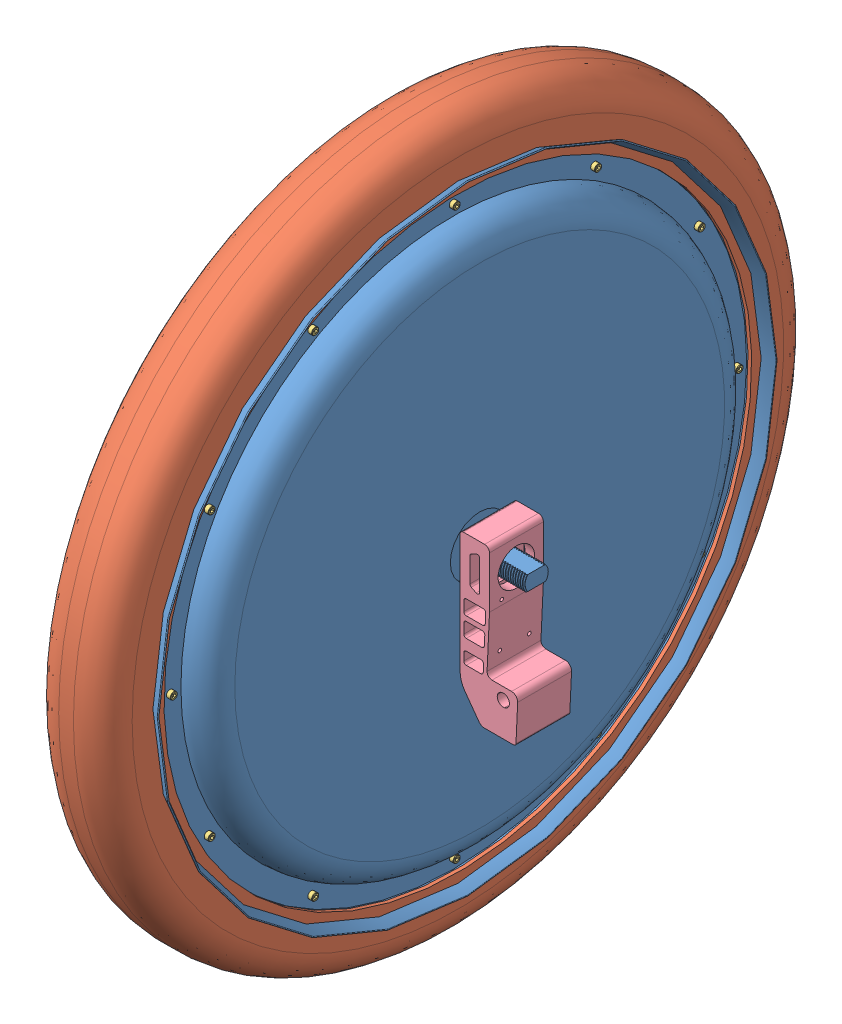
SolidWorks assembly wheel, configuration Default. Lengths in mm.
Overall size (217.51 810.04 810.04).
28 component instances, 5 part files, 9 mates.
Components (placement in the parent):
- motor-1: motor [Default] at origin size (188.73 505.83 505.83)
- tyre-1: tyre [Default] at (-29.8207 0 0) x (1 0 0) z (0 0.587098 0.809516) size (60 580 580)
- socket head cap screw_ai-1: socket head cap screw_ai [HX-SHCS 0.138-40x0.188x0.188-N] at (29.5052 231 0) x (-1 0 0) z (0 0 -1) size (8.28 5.74 5.74)
- socket head cap screw_ai-2: socket head cap screw_ai [HX-SHCS 0.138-40x0.188x0.188-N] at (29.5052 200.0519 -115.5) x (-1 0 0) z (0 -0.5 -0.866025) size (8.28 5.74 5.74)
- socket head cap screw_ai-3: socket head cap screw_ai [HX-SHCS 0.138-40x0.188x0.188-N] at (29.5052 200.0519 115.5) x (-1 0 0) z (0 0.5 -0.866025) size (8.28 5.74 5.74)
- socket head cap screw_ai-4: socket head cap screw_ai [HX-SHCS 0.138-40x0.188x0.188-N] at (29.5052 115.5 200.0519) x (-1 0 0) z (0 0.866025 -0.5) size (8.28 5.74 5.74)
- socket head cap screw_ai-5: socket head cap screw_ai [HX-SHCS 0.138-40x0.188x0.188-N] at (29.5052 0 231) x (-1 0 0) z (0 1 0) size (8.28 5.74 5.74)
- socket head cap screw_ai-6: socket head cap screw_ai [HX-SHCS 0.138-40x0.188x0.188-N] at (29.5052 -115.5 200.0519) x (-1 0 0) z (0 0.866025 0.5) size (8.28 5.74 5.74)
- socket head cap screw_ai-7: socket head cap screw_ai [HX-SHCS 0.138-40x0.188x0.188-N] at (29.5052 -200.0519 115.5) x (-1 0 0) z (0 0.5 0.866025) size (8.28 5.74 5.74)
- socket head cap screw_ai-8: socket head cap screw_ai [HX-SHCS 0.138-40x0.188x0.188-N] at (29.5052 -231 0) x (-1 0 0) z (0 0 1) size (8.28 5.74 5.74)
- socket head cap screw_ai-9: socket head cap screw_ai [HX-SHCS 0.138-40x0.188x0.188-N] at (29.5052 -200.0519 -115.5) x (-1 0 0) z (0 -0.5 0.866025) size (8.28 5.74 5.74)
- socket head cap screw_ai-10: socket head cap screw_ai [HX-SHCS 0.138-40x0.188x0.188-N] at (29.5052 -115.5 -200.0519) x (-1 0 0) z (0 -0.866025 0.5) size (8.28 5.74 5.74)
- socket head cap screw_ai-11: socket head cap screw_ai [HX-SHCS 0.138-40x0.188x0.188-N] at (29.5052 0 -231) x (-1 0 0) z (0 -1 0) size (8.28 5.74 5.74)
- socket head cap screw_ai-12: socket head cap screw_ai [HX-SHCS 0.138-40x0.188x0.188-N] at (29.5052 115.5 -200.0519) x (-1 0 0) z (0 -0.866025 -0.5) size (8.28 5.74 5.74)
- socket head cap screw_ai-13: socket head cap screw_ai [HX-SHCS 0.138-40x0.188x0.188-N] at (-29.5052 231 0) size (8.28 5.74 5.74)
- socket head cap screw_ai-14: socket head cap screw_ai [HX-SHCS 0.138-40x0.188x0.188-N] at (-29.5052 200.0519 -115.5) x (1 0 0) z (0 0.5 0.866025) size (8.28 5.74 5.74)
- socket head cap screw_ai-15: socket head cap screw_ai [HX-SHCS 0.138-40x0.188x0.188-N] at (-29.5052 200.0519 115.5) x (1 0 0) z (0 -0.5 0.866025) size (8.28 5.74 5.74)
- socket head cap screw_ai-16: socket head cap screw_ai [HX-SHCS 0.138-40x0.188x0.188-N] at (-29.5052 115.5 200.0519) x (1 0 0) z (0 -0.866025 0.5) size (8.28 5.74 5.74)
- socket head cap screw_ai-17: socket head cap screw_ai [HX-SHCS 0.138-40x0.188x0.188-N] at (-29.5052 0 231) x (1 0 0) z (0 -1 0) size (8.28 5.74 5.74)
- socket head cap screw_ai-18: socket head cap screw_ai [HX-SHCS 0.138-40x0.188x0.188-N] at (-29.5052 -115.5 200.0519) x (1 0 0) z (0 -0.866025 -0.5) size (8.28 5.74 5.74)
- socket head cap screw_ai-19: socket head cap screw_ai [HX-SHCS 0.138-40x0.188x0.188-N] at (-29.5052 -200.0519 115.5) x (1 0 0) z (0 -0.5 -0.866025) size (8.28 5.74 5.74)
- socket head cap screw_ai-20: socket head cap screw_ai [HX-SHCS 0.138-40x0.188x0.188-N] at (-29.5052 -231 0) x (1 0 0) z (0 0 -1) size (8.28 5.74 5.74)
- socket head cap screw_ai-21: socket head cap screw_ai [HX-SHCS 0.138-40x0.188x0.188-N] at (-29.5052 -200.0519 -115.5) x (1 0 0) z (0 0.5 -0.866025) size (8.28 5.74 5.74)
- socket head cap screw_ai-22: socket head cap screw_ai [HX-SHCS 0.138-40x0.188x0.188-N] at (-29.5052 -115.5 -200.0519) x (1 0 0) z (0 0.866025 -0.5) size (8.28 5.74 5.74)
- socket head cap screw_ai-23: socket head cap screw_ai [HX-SHCS 0.138-40x0.188x0.188-N] at (-29.5052 0 -231) x (1 0 0) z (0 1 0) size (8.28 5.74 5.74)
- socket head cap screw_ai-24: socket head cap screw_ai [HX-SHCS 0.138-40x0.188x0.188-N] at (-29.5052 115.5 -200.0519) x (1 0 0) z (0 0.866025 0.5) size (8.28 5.74 5.74)
- pedal hanger1-1: pedal hanger1 [Default] at (128.9328 -140.4403 -75.0082) x (0.997537 -0.070149 0) z (-0.006861 -0.09757 0.995205) size (54.31 133.41 56.48)
- pedal hanger2-1: pedal hanger2 [Default] at (-128.9328 -140.4403 75.0082) x (-0.997537 -0.070149 0) z (0.006861 -0.09757 -0.995205) size (54.31 133.41 56.48)
Mates (geometry in assembly coordinates):
- Concentric1: concentric aligned: circle of motor-1; cylinder of tyre-1 through (30.1793 0 0) axis (-1 0 0) radius 290
- Concentric21: concentric aligned: cylinder of motor-1 through (16 231 0) axis (1 0 0) radius 2; cylinder of socket head cap screw_ai-1 through (61.2552 231 0) axis (1 0 0) radius 1.7526
- Coincident11: coincident anti-aligned: plane of motor-1 through (26 222 0) normal (1 0 0); plane of socket head cap screw_ai-1 through (26 233.8702 0) normal (-1 0 0)
- Coincident12: coincident anti-aligned: plane of motor-1 through (54 0 0) normal (1 0 0); plane of pedal arm1-1 through (54 -75.003 22) normal (-1 0 0)
- Parallel1: parallel aligned: plane of motor-1 through (54 6 0) normal (0 1 0); plane of pedal arm1-1 through (80.0079 -68 22) normal (0 1 0)
- Concentric22: concentric: cylinder of pedal hanger1-1 through (98 0 0) axis (-1 0 0) radius 7
- Coincident16: coincident anti-aligned: plane of motor-1 through (-54 0 0) normal (-1 0 0); plane of pedal arm2-1 through (-54 -75.003 -22) normal (1 0 0)
- Parallel2: parallel aligned: plane of motor-1 through (-54 6 0) normal (0 1 0); plane of pedal arm2-1 through (-80.0079 -68 -22) normal (0 1 0)
- Concentric25: concentric: cylinder of pedal arm2-1 through (-98 0 0) axis (1 0 0) radius 7
